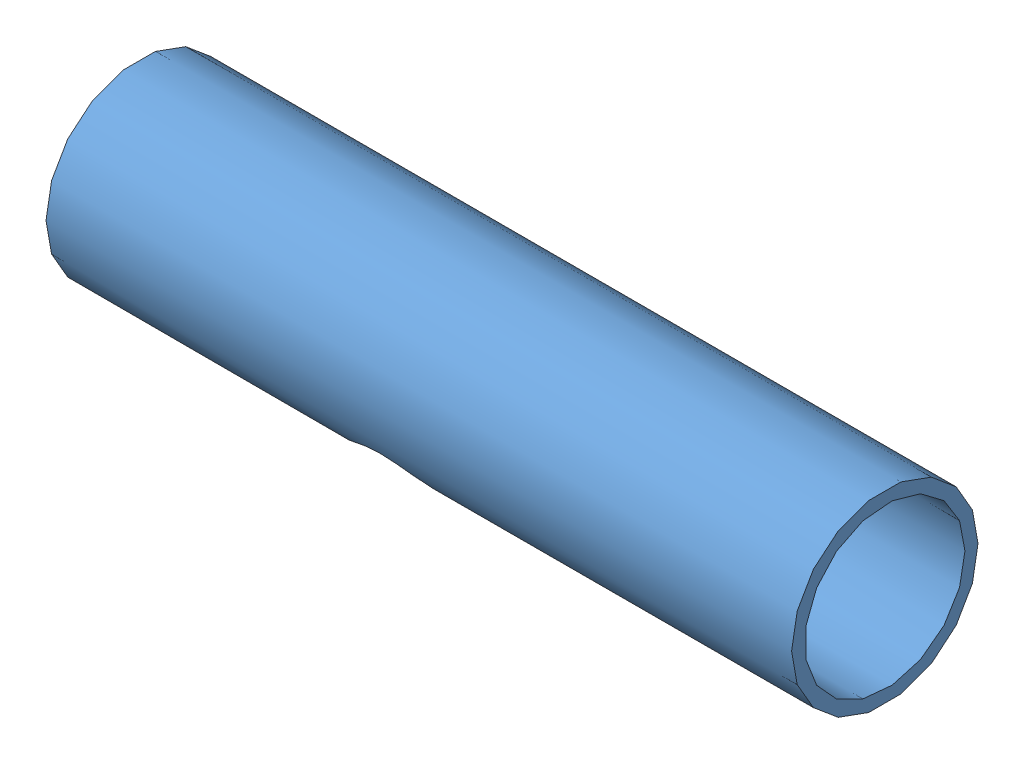
SolidWorks assembly Assem1, configuration Default. Lengths in mm.
Overall size (200 50 50).
2 component instances, 2 part files, 3 mates.
Components (placement in the parent):
- tube-1: tube [Default] at origin size (200 50 50)
- compressed string-1: compressed string [Default] at (9.9524 0 -0.9741) x (0 -1 0) z (0 0 1) size (35.12 54.99 35.12)
Mates (geometry in assembly coordinates):
- Distance1: distance = 10 mm: point of compressed string-1; point of assembly
- Parallel1: parallel aligned: plane of compressed string-1 through (9.9524 0 -0.9741) normal (0 0 1); plane of assembly through (0 0 0) normal (0 0 1)
- Coincident6: coincident anti-aligned: plane of compressed string-1; plane of assembly through (0 0 0) normal (0 1 0)
